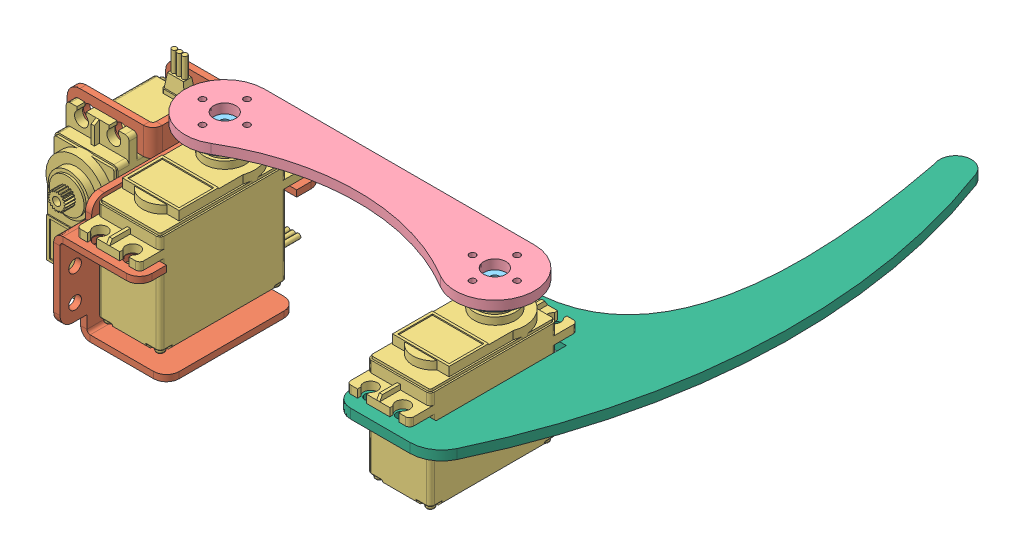
SolidWorks assembly right_leg, configuration Default. Lengths in mm.
Overall size (169.29 66.67 165.5).
10 component instances, 6 part files, 27 mates.
Components (placement in the parent):
- bearing-1: bearing [Default] at (0 0 -48.4217) x (0.00019 1 0) z (0 0 -1) size (9.5 9.5 4)
- coxa-1: coxa [Défaut] at (14.87 -10 -48.4217) x (0 1 0) z (0 0 1) size (58 27 37.5)
- servo-1: servo [Default] at (9.906 -10.287 -21.3907) x (-1 0 0) z (0 1 0) size (19.81 42.14 58.23)
- coxa-2: coxa [Défaut] at (14.87 -25.75 -13.1717) x (0 0 1) z (0 1 0) size (58 27 37.5)
- servo-2: servo [Default] at (39.646 1.281 -12.8847) x (-1 0 0) z (0 0 -1) size (19.81 42.14 58.23)
- femur-1: femur [Default] at (72.24 24.6717 -23.1717) x (-1 0 0) z (0 1 0) size (110 25 3)
- horn-1: horn [Default] at (29.74 24.6717 -23.1717) x (-1 0 0) z (0 -1 0) size (20 20 4.5)
- horn-2: horn [Default] at (114.74 24.6717 -23.1717) x (-1 0 0) z (0 -1 0) size (20 20 4.5)
- servo-3: servo [Default] at (124.646 1.281 -12.8847) x (-1 0 0) z (0 0 -1) size (19.81 42.14 58.23)
- tibia-1: tibia [Default] at (114.74 7.25 -23.1717) x (0 0 -1) z (0 -1 0) size (165.5 56.86 3.1)
Mates (geometry in assembly coordinates):
- Concentric1: concentric anti-aligned: cylinder of bearing-1 through (0 0 -48.4217) axis (0 0 -1) radius 1; cylinder of coxa-1 through (0 0 -46.4217) axis (0 0 1) radius 1.25
- Coincident2: coincident anti-aligned: plane of bearing-1 through (0 0 -48.4217) normal (0 0 1); plane of coxa-1 through (-12.13 10.5 -48.4217) normal (0 0 -1)
- Concentric2: concentric aligned: cylinder of coxa-1 through (0 0 -46.4217) axis (0 0 1) radius 1.25; cylinder of servo-1 through (0 0 -9.6666) axis (0 0 1) radius 1.27
- Coincident4: coincident anti-aligned: plane of coxa-1 through (14.87 -10 -15.4217) normal (0 0 1); plane of servo-1 through (-9.906 -10.287 -15.4217) normal (0 0 -1)
- Parallel1: parallel anti-aligned: plane of coxa-1 through (12.87 10.5 -48.4217) normal (-1 0 0); plane of servo-1 through (9.906 -10.287 -21.3907) normal (1 0 0)
- Concentric3: concentric anti-aligned: cylinder of coxa-1 through (12.87 -0.25 -22.9217) axis (-1 0 0) radius 4; cylinder of coxa-2 through (16.87 -0.25 -22.9217) axis (1 0 0) radius 4
- Concentric4: concentric anti-aligned: cylinder of coxa-1 through (12.87 -0.25 -15.9217) axis (-1 0 0) radius 1.25; cylinder of coxa-2 through (16.87 -0.25 -15.9217) axis (1 0 0) radius 1.25
- Coincident7: coincident anti-aligned: plane of coxa-1 through (14.87 10.5 -48.4217) normal (1 0 0); plane of coxa-2 through (14.87 -25.75 7.3283) normal (-1 0 0)
- Concentric5: concentric aligned: cylinder of coxa-2 through (29.74 -23.75 -23.1717) axis (0 1 0) radius 1.25; cylinder of servo-2 through (29.74 13.0051 -23.1717) axis (0 1 0) radius 1.27
- Coincident8: coincident anti-aligned: plane of coxa-2 through (14.87 7.25 -13.1717) normal (0 1 0); plane of servo-2 through (19.834 7.25 -12.8847) normal (0 -1 0)
- Parallel2: parallel anti-aligned: plane of coxa-2 through (16.87 -25.75 7.3283) normal (1 0 0); plane of servo-2 through (19.834 1.281 -12.8847) normal (-1 0 0)
- Concentric6: concentric anti-aligned: cylinder of femur-1 through (114.74 27.6717 -23.1717) axis (0 -1 0) radius 3.5; cylinder of horn-2 through (114.74 22.6717 -23.1717) axis (0 1 0) radius 1.5
- Concentric10: concentric anti-aligned: cylinder of femur-1 through (121.74 27.6717 -23.1717) axis (0 -1 0) radius 1; cylinder of horn-2 through (121.74 22.6717 -23.1717) axis (0 1 0) radius 1
- Coincident9: coincident anti-aligned: plane of femur-1 through (114.74 24.6717 -23.1717) normal (0 -1 0); plane of horn-2 through (114.74 24.6717 -23.1717) normal (0 1 0)
- Concentric11: concentric anti-aligned: cylinder of femur-1 through (29.74 27.6717 -23.1717) axis (0 -1 0) radius 3.5; cylinder of horn-1 through (29.74 22.6717 -23.1717) axis (0 1 0) radius 1.5
- Concentric12: concentric anti-aligned: cylinder of femur-1 through (22.74 27.6717 -23.1717) axis (0 -1 0) radius 1; cylinder of horn-1 through (22.74 22.6717 -23.1717) axis (0 1 0) radius 1
- Coincident10: coincident anti-aligned: plane of femur-1 through (114.74 24.6717 -23.1717) normal (0 -1 0); plane of horn-1 through (29.74 24.6717 -23.1717) normal (0 1 0)
- Concentric13: concentric aligned: cylinder of servo-2 through (29.74 13.0051 -23.1717) axis (0 1 0) radius 1.27; cylinder of horn-1 through (29.74 22.6717 -23.1717) axis (0 1 0) radius 1.5
- Coincident11: coincident anti-aligned: plane of servo-2 through (19.834 22.6717 -12.8847) normal (0 1 0); plane of horn-1 through (29.74 22.6717 -23.1717) normal (0 -1 0)
- Concentric14: concentric aligned: cylinder of horn-2 through (114.74 22.6717 -23.1717) axis (0 1 0) radius 1.5; cylinder of servo-3 through (114.74 13.0051 -23.1717) axis (0 1 0) radius 1.27
- Coincident12: coincident anti-aligned: plane of horn-2 through (114.74 22.6717 -23.1717) normal (0 -1 0); plane of servo-3 through (104.834 22.6717 -12.8847) normal (0 1 0)
- Coincident13: coincident anti-aligned: plane of servo-3 through (104.834 7.25 -12.8847) normal (0 -1 0); plane of tibia-1 through (-42.8373 7.25 -74.6842) normal (0 1 0)
- Parallel5: parallel anti-aligned: plane of servo-3 through (124.646 1.281 -12.8847) normal (1 0 0); plane of tibia-1 through (126.74 4.25 7.3283) normal (-1 0 0)
- Coincident15: coincident aligned: line of servo-3 through (114.74 16.5972 -23.1717) axis (0 1 0); line of tibia-1 through (114.74 7.25 -23.1717) axis (0 1 0)
- Coincident21: coordinate: point of servo-1
- Coincident22: coordinate: unknown of servo-2; unknown of horn-1
- Coincident24: coordinate: unknown of horn-2; unknown of servo-3
